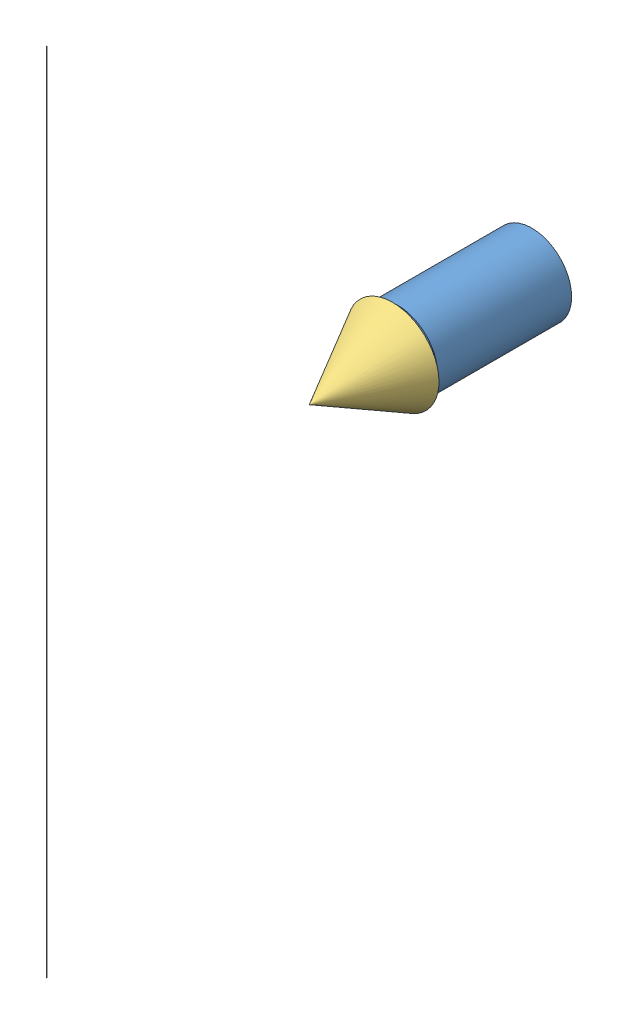
SolidWorks assembly Assem1, configuration Default. Lengths in mm.
Overall size (100.02 304.8 104.44).
3 component instances, 3 part files, 0 mates.
Components (placement in the parent):
- Part1-1: Part1 [Default] at (-23.8289 -36.2442 -49.2398) size (30 30 50.6)
- Wire-1: Wire [Default] at (-46.3971 -237.0441 0.1818) size (0.2 304.8 0.2)
- Part3-4: Part3 [Default] at (-26.6425 -20.9294 34.1723) x (0.274405 -0.961523 -0.013276) z (-0.961612 -0.27441 -0.001435) size (34.61 31.75 34.61)
